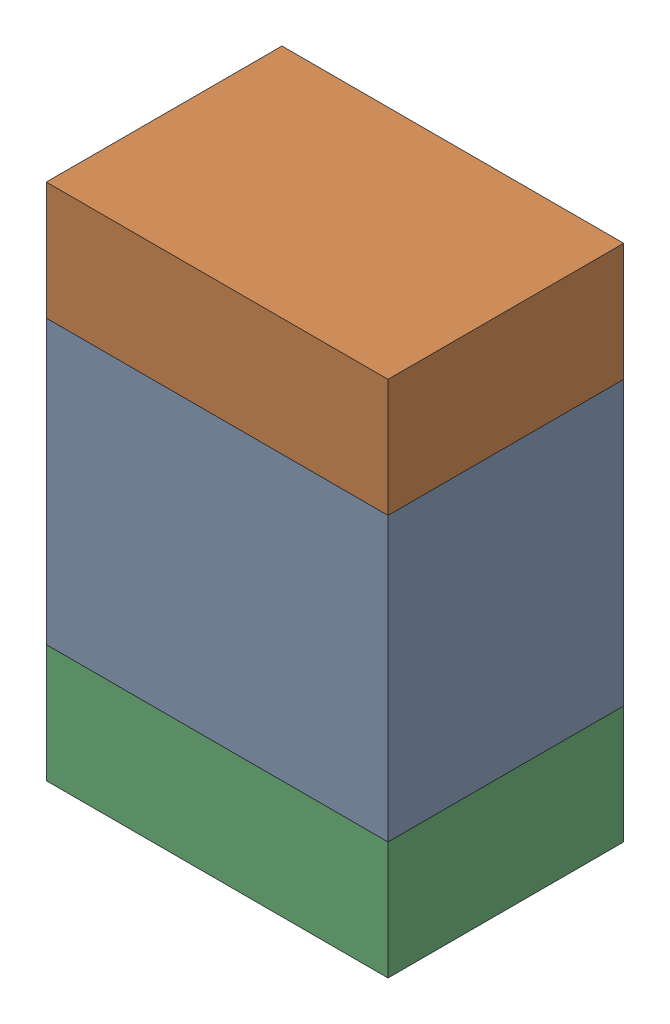
SolidWorks assembly C8-2, configuration Default. Lengths in mm.
Overall size (1.45 2.2 1).
6 component instances, 2 part files, 0 mates.
Components (placement in the parent):
- 959207984-2-1: 959207984-2 [Default] at (115.697 77.2073 0) size (1.45 1.2 1)
  - Extruded-80-1: Extruded-80 [Default] at origin size (1.45 1.2 1)
- 959207848-2-1: 959207848-2 [Default] at (115.697 78.0573 0) size (1.45 0.5 1)
  - Extruded-81-1: Extruded-81 [Default] at origin size (1.45 0.5 1)
- 959207848-2-2: 959207848-2 [Default] at (115.697 76.3573 0) size (1.45 0.5 1)
  - Extruded-81-1: Extruded-81 [Default] at origin size (1.45 0.5 1)
